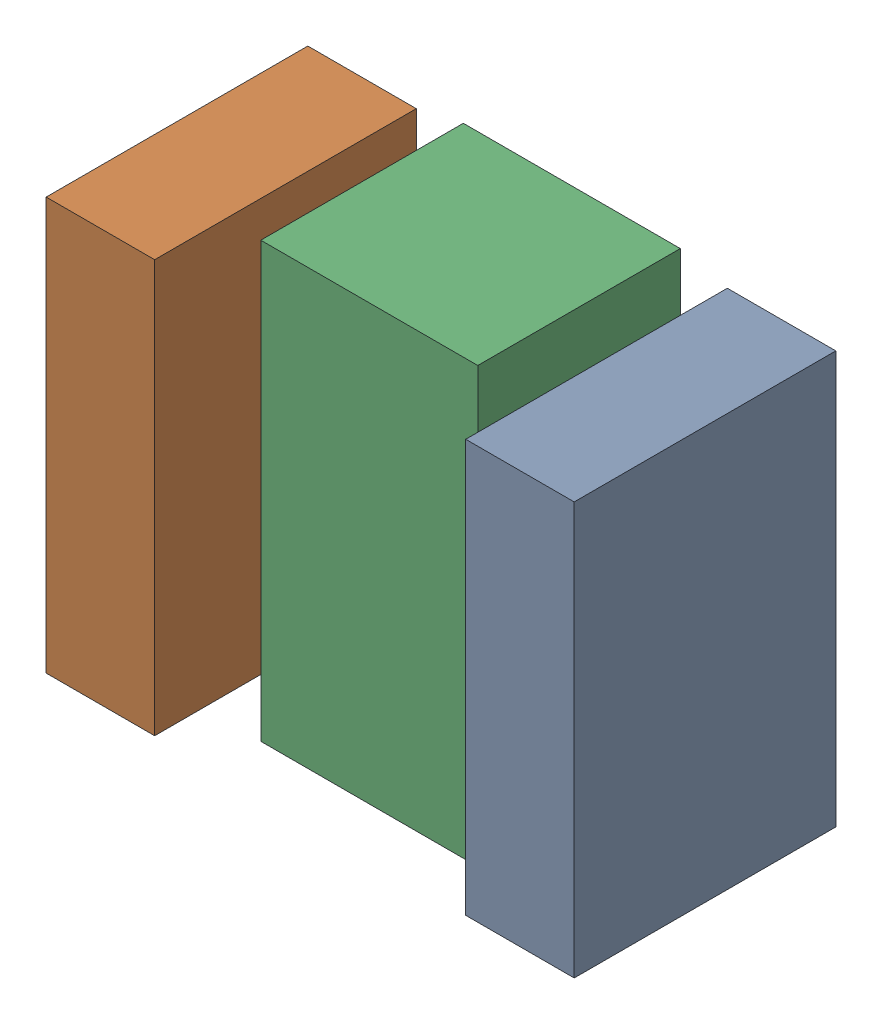
SolidWorks assembly C11_Motor_9Kanaloa_v2.0.0_Motor, configuration Default. Lengths in mm.
Overall size (3.65 3 1.81).
6 component instances, 2 part files, 0 mates.
Components (placement in the parent):
- 334788400-1: 334788400 [Default] at (36.205 163.83 0) size (0.75 2.85 1.81)
  - Extruded_5-1: Extruded_5 [Default] at origin size (0.75 2.85 1.81)
- 334788400-2: 334788400 [Default] at (33.305 163.83 0) size (0.75 2.85 1.81)
  - Extruded_5-1: Extruded_5 [Default] at origin size (0.75 2.85 1.81)
- 334788656-1: 334788656 [Default] at (34.755 163.83 0) size (1.5 3 1.4)
  - Extruded_1-1: Extruded_1 [Default] at origin size (1.5 3 1.4)
